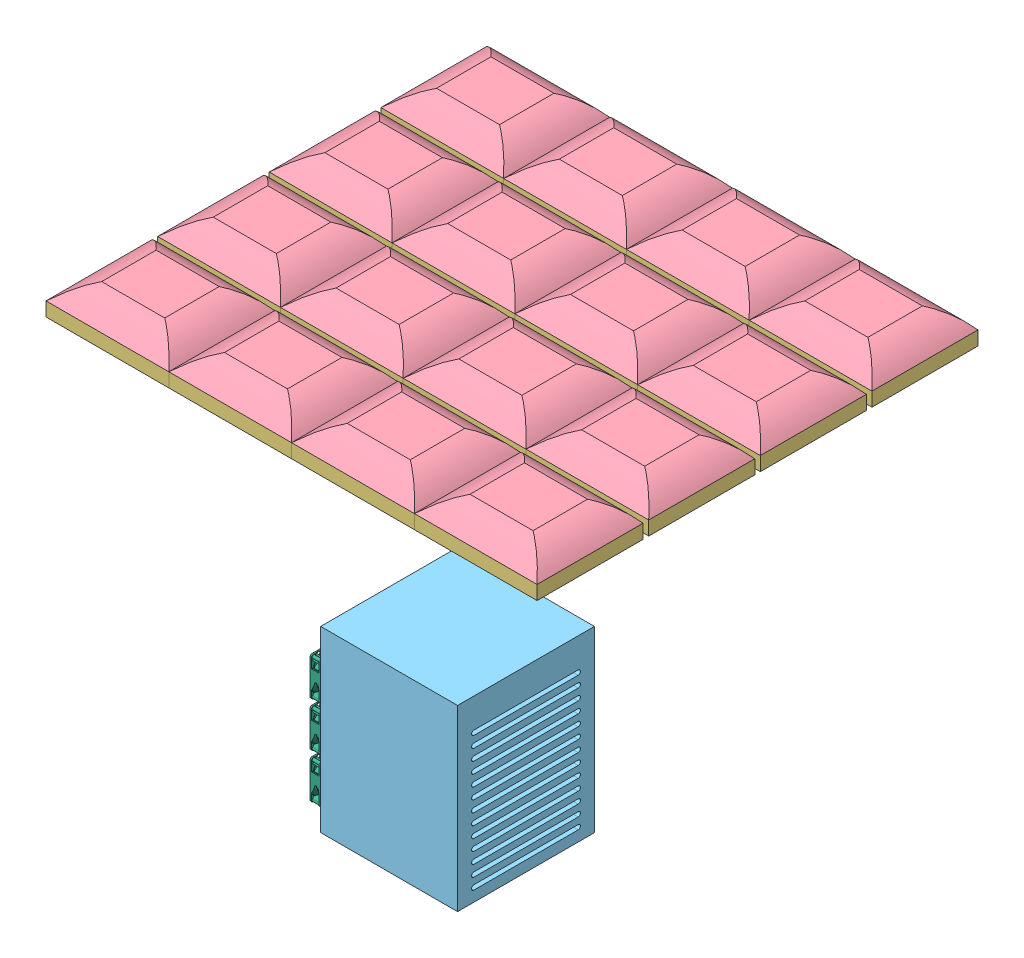
SolidWorks assembly Сборка2, configuration По умолчанию. Lengths in mm.
Overall size (44 41.09 39.5).
203 component instances, 7 part files, 2 mates.
Components (placement in the parent):
- Сборка1-8: Сборка1 [По умолчанию] at (6.9348 -5.2924 17.6089) size (11 2.93 9.5)
  - Ntrcnjkbn-1: Ntrcnjkbn [По умолчанию] at (-3.4337 12.5234 -9.2376) size (10.5 0.3 9)
  - Антенна-1: Антенна [По умолчанию] at (-7.1837 12.8234 -11.7376) size (2 0.4 3.88)
  - Антенна-2: Антенна [По умолчанию] at (-4.6837 12.8234 -11.7376) size (2 0.4 3.88)
  - Антенна-3: Антенна [По умолчанию] at (-2.1837 12.8234 -11.7376) size (2 0.4 3.88)
  - Антенна-4: Антенна [По умолчанию] at (0.3163 12.8234 -11.7376) size (2 0.4 3.88)
  - Антенна-5: Антенна [По умолчанию] at (0.3163 12.8234 -6.7376) x (-1 0 0) z (0 0 -1) size (2 0.4 3.88)
  - Антенна-6: Антенна [По умолчанию] at (-2.1837 12.8234 -6.7376) x (-1 0 0) z (0 0 -1) size (2 0.4 3.88)
  - Антенна-7: Антенна [По умолчанию] at (-4.6837 12.8234 -6.7376) x (-1 0 0) z (0 0 -1) size (2 0.4 3.88)
  - Антенна-8: Антенна [По умолчанию] at (-7.1837 12.8234 -6.7376) x (-1 0 0) z (0 0 -1) size (2 0.4 3.88)
  - Корпус-1: Корпус [По умолчанию] at (-3.4337 11.7734 -9.2035) size (11 1.25 9.5)
  - Крышка-1: Крышка [По умолчанию] at (-3.4337 13.0234 -9.2035) size (11 1.68 9.5)
- Сборка1-9: Сборка1 [По умолчанию] at (6.9348 -5.2924 27.6089) size (11 2.93 9.5)
  - Ntrcnjkbn-1: Ntrcnjkbn [По умолчанию] at (-3.4337 12.5234 -9.2376) size (10.5 0.3 9)
  - Антенна-1: Антенна [По умолчанию] at (-7.1837 12.8234 -11.7376) size (2 0.4 3.88)
  - Антенна-2: Антенна [По умолчанию] at (-4.6837 12.8234 -11.7376) size (2 0.4 3.88)
  - Антенна-3: Антенна [По умолчанию] at (-2.1837 12.8234 -11.7376) size (2 0.4 3.88)
  - Антенна-4: Антенна [По умолчанию] at (0.3163 12.8234 -11.7376) size (2 0.4 3.88)
  - Антенна-5: Антенна [По умолчанию] at (0.3163 12.8234 -6.7376) x (-1 0 0) z (0 0 -1) size (2 0.4 3.88)
  - Антенна-6: Антенна [По умолчанию] at (-2.1837 12.8234 -6.7376) x (-1 0 0) z (0 0 -1) size (2 0.4 3.88)
  - Антенна-7: Антенна [По умолчанию] at (-4.6837 12.8234 -6.7376) x (-1 0 0) z (0 0 -1) size (2 0.4 3.88)
  - Антенна-8: Антенна [По умолчанию] at (-7.1837 12.8234 -6.7376) x (-1 0 0) z (0 0 -1) size (2 0.4 3.88)
  - Корпус-1: Корпус [По умолчанию] at (-3.4337 11.7734 -9.2035) size (11 1.25 9.5)
  - Крышка-1: Крышка [По умолчанию] at (-3.4337 13.0234 -9.2035) size (11 1.68 9.5)
- Сборка1-10: Сборка1 [По умолчанию] at (6.9348 -5.2924 37.6089) size (11 2.93 9.5)
  - Ntrcnjkbn-1: Ntrcnjkbn [По умолчанию] at (-3.4337 12.5234 -9.2376) size (10.5 0.3 9)
  - Антенна-1: Антенна [По умолчанию] at (-7.1837 12.8234 -11.7376) size (2 0.4 3.88)
  - Антенна-2: Антенна [По умолчанию] at (-4.6837 12.8234 -11.7376) size (2 0.4 3.88)
  - Антенна-3: Антенна [По умолчанию] at (-2.1837 12.8234 -11.7376) size (2 0.4 3.88)
  - Антенна-4: Антенна [По умолчанию] at (0.3163 12.8234 -11.7376) size (2 0.4 3.88)
  - Антенна-5: Антенна [По умолчанию] at (0.3163 12.8234 -6.7376) x (-1 0 0) z (0 0 -1) size (2 0.4 3.88)
  - Антенна-6: Антенна [По умолчанию] at (-2.1837 12.8234 -6.7376) x (-1 0 0) z (0 0 -1) size (2 0.4 3.88)
  - Антенна-7: Антенна [По умолчанию] at (-4.6837 12.8234 -6.7376) x (-1 0 0) z (0 0 -1) size (2 0.4 3.88)
  - Антенна-8: Антенна [По умолчанию] at (-7.1837 12.8234 -6.7376) x (-1 0 0) z (0 0 -1) size (2 0.4 3.88)
  - Корпус-1: Корпус [По умолчанию] at (-3.4337 11.7734 -9.2035) size (11 1.25 9.5)
  - Крышка-1: Крышка [По умолчанию] at (-3.4337 13.0234 -9.2035) size (11 1.68 9.5)
- Сборка1-11: Сборка1 [По умолчанию] at (6.9348 -5.2924 47.6089) size (11 2.93 9.5)
  - Ntrcnjkbn-1: Ntrcnjkbn [По умолчанию] at (-3.4337 12.5234 -9.2376) size (10.5 0.3 9)
  - Антенна-1: Антенна [По умолчанию] at (-7.1837 12.8234 -11.7376) size (2 0.4 3.88)
  - Антенна-2: Антенна [По умолчанию] at (-4.6837 12.8234 -11.7376) size (2 0.4 3.88)
  - Антенна-3: Антенна [По умолчанию] at (-2.1837 12.8234 -11.7376) size (2 0.4 3.88)
  - Антенна-4: Антенна [По умолчанию] at (0.3163 12.8234 -11.7376) size (2 0.4 3.88)
  - Антенна-5: Антенна [По умолчанию] at (0.3163 12.8234 -6.7376) x (-1 0 0) z (0 0 -1) size (2 0.4 3.88)
  - Антенна-6: Антенна [По умолчанию] at (-2.1837 12.8234 -6.7376) x (-1 0 0) z (0 0 -1) size (2 0.4 3.88)
  - Антенна-7: Антенна [По умолчанию] at (-4.6837 12.8234 -6.7376) x (-1 0 0) z (0 0 -1) size (2 0.4 3.88)
  - Антенна-8: Антенна [По умолчанию] at (-7.1837 12.8234 -6.7376) x (-1 0 0) z (0 0 -1) size (2 0.4 3.88)
  - Корпус-1: Корпус [По умолчанию] at (-3.4337 11.7734 -9.2035) size (11 1.25 9.5)
  - Крышка-1: Крышка [По умолчанию] at (-3.4337 13.0234 -9.2035) size (11 1.68 9.5)
- Сборка1-12: Сборка1 [По умолчанию] at (17.9348 -5.2924 17.6089) size (11 2.93 9.5)
  - Ntrcnjkbn-1: Ntrcnjkbn [По умолчанию] at (-3.4337 12.5234 -9.2376) size (10.5 0.3 9)
  - Антенна-1: Антенна [По умолчанию] at (-7.1837 12.8234 -11.7376) size (2 0.4 3.88)
  - Антенна-2: Антенна [По умолчанию] at (-4.6837 12.8234 -11.7376) size (2 0.4 3.88)
  - Антенна-3: Антенна [По умолчанию] at (-2.1837 12.8234 -11.7376) size (2 0.4 3.88)
  - Антенна-4: Антенна [По умолчанию] at (0.3163 12.8234 -11.7376) size (2 0.4 3.88)
  - Антенна-5: Антенна [По умолчанию] at (0.3163 12.8234 -6.7376) x (-1 0 0) z (0 0 -1) size (2 0.4 3.88)
  - Антенна-6: Антенна [По умолчанию] at (-2.1837 12.8234 -6.7376) x (-1 0 0) z (0 0 -1) size (2 0.4 3.88)
  - Антенна-7: Антенна [По умолчанию] at (-4.6837 12.8234 -6.7376) x (-1 0 0) z (0 0 -1) size (2 0.4 3.88)
  - Антенна-8: Антенна [По умолчанию] at (-7.1837 12.8234 -6.7376) x (-1 0 0) z (0 0 -1) size (2 0.4 3.88)
  - Корпус-1: Корпус [По умолчанию] at (-3.4337 11.7734 -9.2035) size (11 1.25 9.5)
  - Крышка-1: Крышка [По умолчанию] at (-3.4337 13.0234 -9.2035) size (11 1.68 9.5)
- Сборка1-13: Сборка1 [По умолчанию] at (17.9348 -5.2924 27.6089) size (11 2.93 9.5)
  - Ntrcnjkbn-1: Ntrcnjkbn [По умолчанию] at (-3.4337 12.5234 -9.2376) size (10.5 0.3 9)
  - Антенна-1: Антенна [По умолчанию] at (-7.1837 12.8234 -11.7376) size (2 0.4 3.88)
  - Антенна-2: Антенна [По умолчанию] at (-4.6837 12.8234 -11.7376) size (2 0.4 3.88)
  - Антенна-3: Антенна [По умолчанию] at (-2.1837 12.8234 -11.7376) size (2 0.4 3.88)
  - Антенна-4: Антенна [По умолчанию] at (0.3163 12.8234 -11.7376) size (2 0.4 3.88)
  - Антенна-5: Антенна [По умолчанию] at (0.3163 12.8234 -6.7376) x (-1 0 0) z (0 0 -1) size (2 0.4 3.88)
  - Антенна-6: Антенна [По умолчанию] at (-2.1837 12.8234 -6.7376) x (-1 0 0) z (0 0 -1) size (2 0.4 3.88)
  - Антенна-7: Антенна [По умолчанию] at (-4.6837 12.8234 -6.7376) x (-1 0 0) z (0 0 -1) size (2 0.4 3.88)
  - Антенна-8: Антенна [По умолчанию] at (-7.1837 12.8234 -6.7376) x (-1 0 0) z (0 0 -1) size (2 0.4 3.88)
  - Корпус-1: Корпус [По умолчанию] at (-3.4337 11.7734 -9.2035) size (11 1.25 9.5)
  - Крышка-1: Крышка [По умолчанию] at (-3.4337 13.0234 -9.2035) size (11 1.68 9.5)
- Сборка1-14: Сборка1 [По умолчанию] at (17.9348 -5.2924 37.6089) size (11 2.93 9.5)
  - Ntrcnjkbn-1: Ntrcnjkbn [По умолчанию] at (-3.4337 12.5234 -9.2376) size (10.5 0.3 9)
  - Антенна-1: Антенна [По умолчанию] at (-7.1837 12.8234 -11.7376) size (2 0.4 3.88)
  - Антенна-2: Антенна [По умолчанию] at (-4.6837 12.8234 -11.7376) size (2 0.4 3.88)
  - Антенна-3: Антенна [По умолчанию] at (-2.1837 12.8234 -11.7376) size (2 0.4 3.88)
  - Антенна-4: Антенна [По умолчанию] at (0.3163 12.8234 -11.7376) size (2 0.4 3.88)
  - Антенна-5: Антенна [По умолчанию] at (0.3163 12.8234 -6.7376) x (-1 0 0) z (0 0 -1) size (2 0.4 3.88)
  - Антенна-6: Антенна [По умолчанию] at (-2.1837 12.8234 -6.7376) x (-1 0 0) z (0 0 -1) size (2 0.4 3.88)
  - Антенна-7: Антенна [По умолчанию] at (-4.6837 12.8234 -6.7376) x (-1 0 0) z (0 0 -1) size (2 0.4 3.88)
  - Антенна-8: Антенна [По умолчанию] at (-7.1837 12.8234 -6.7376) x (-1 0 0) z (0 0 -1) size (2 0.4 3.88)
  - Корпус-1: Корпус [По умолчанию] at (-3.4337 11.7734 -9.2035) size (11 1.25 9.5)
  - Крышка-1: Крышка [По умолчанию] at (-3.4337 13.0234 -9.2035) size (11 1.68 9.5)
- Сборка1-15: Сборка1 [По умолчанию] at (17.9348 -5.2924 47.6089) size (11 2.93 9.5)
  - Ntrcnjkbn-1: Ntrcnjkbn [По умолчанию] at (-3.4337 12.5234 -9.2376) size (10.5 0.3 9)
  - Антенна-1: Антенна [По умолчанию] at (-7.1837 12.8234 -11.7376) size (2 0.4 3.88)
  - Антенна-2: Антенна [По умолчанию] at (-4.6837 12.8234 -11.7376) size (2 0.4 3.88)
  - Антенна-3: Антенна [По умолчанию] at (-2.1837 12.8234 -11.7376) size (2 0.4 3.88)
  - Антенна-4: Антенна [По умолчанию] at (0.3163 12.8234 -11.7376) size (2 0.4 3.88)
  - Антенна-5: Антенна [По умолчанию] at (0.3163 12.8234 -6.7376) x (-1 0 0) z (0 0 -1) size (2 0.4 3.88)
  - Антенна-6: Антенна [По умолчанию] at (-2.1837 12.8234 -6.7376) x (-1 0 0) z (0 0 -1) size (2 0.4 3.88)
  - Антенна-7: Антенна [По умолчанию] at (-4.6837 12.8234 -6.7376) x (-1 0 0) z (0 0 -1) size (2 0.4 3.88)
  - Антенна-8: Антенна [По умолчанию] at (-7.1837 12.8234 -6.7376) x (-1 0 0) z (0 0 -1) size (2 0.4 3.88)
  - Корпус-1: Корпус [По умолчанию] at (-3.4337 11.7734 -9.2035) size (11 1.25 9.5)
  - Крышка-1: Крышка [По умолчанию] at (-3.4337 13.0234 -9.2035) size (11 1.68 9.5)
- Сборка1-16: Сборка1 [По умолчанию] at (28.9348 -5.2924 17.6089) size (11 2.93 9.5)
  - Ntrcnjkbn-1: Ntrcnjkbn [По умолчанию] at (-3.4337 12.5234 -9.2376) size (10.5 0.3 9)
  - Антенна-1: Антенна [По умолчанию] at (-7.1837 12.8234 -11.7376) size (2 0.4 3.88)
  - Антенна-2: Антенна [По умолчанию] at (-4.6837 12.8234 -11.7376) size (2 0.4 3.88)
  - Антенна-3: Антенна [По умолчанию] at (-2.1837 12.8234 -11.7376) size (2 0.4 3.88)
  - Антенна-4: Антенна [По умолчанию] at (0.3163 12.8234 -11.7376) size (2 0.4 3.88)
  - Антенна-5: Антенна [По умолчанию] at (0.3163 12.8234 -6.7376) x (-1 0 0) z (0 0 -1) size (2 0.4 3.88)
  - Антенна-6: Антенна [По умолчанию] at (-2.1837 12.8234 -6.7376) x (-1 0 0) z (0 0 -1) size (2 0.4 3.88)
  - Антенна-7: Антенна [По умолчанию] at (-4.6837 12.8234 -6.7376) x (-1 0 0) z (0 0 -1) size (2 0.4 3.88)
  - Антенна-8: Антенна [По умолчанию] at (-7.1837 12.8234 -6.7376) x (-1 0 0) z (0 0 -1) size (2 0.4 3.88)
  - Корпус-1: Корпус [По умолчанию] at (-3.4337 11.7734 -9.2035) size (11 1.25 9.5)
  - Крышка-1: Крышка [По умолчанию] at (-3.4337 13.0234 -9.2035) size (11 1.68 9.5)
- Сборка1-17: Сборка1 [По умолчанию] at (28.9348 -5.2924 27.6089) size (11 2.93 9.5)
  - Ntrcnjkbn-1: Ntrcnjkbn [По умолчанию] at (-3.4337 12.5234 -9.2376) size (10.5 0.3 9)
  - Антенна-1: Антенна [По умолчанию] at (-7.1837 12.8234 -11.7376) size (2 0.4 3.88)
  - Антенна-2: Антенна [По умолчанию] at (-4.6837 12.8234 -11.7376) size (2 0.4 3.88)
  - Антенна-3: Антенна [По умолчанию] at (-2.1837 12.8234 -11.7376) size (2 0.4 3.88)
  - Антенна-4: Антенна [По умолчанию] at (0.3163 12.8234 -11.7376) size (2 0.4 3.88)
  - Антенна-5: Антенна [По умолчанию] at (0.3163 12.8234 -6.7376) x (-1 0 0) z (0 0 -1) size (2 0.4 3.88)
  - Антенна-6: Антенна [По умолчанию] at (-2.1837 12.8234 -6.7376) x (-1 0 0) z (0 0 -1) size (2 0.4 3.88)
  - Антенна-7: Антенна [По умолчанию] at (-4.6837 12.8234 -6.7376) x (-1 0 0) z (0 0 -1) size (2 0.4 3.88)
  - Антенна-8: Антенна [По умолчанию] at (-7.1837 12.8234 -6.7376) x (-1 0 0) z (0 0 -1) size (2 0.4 3.88)
  - Корпус-1: Корпус [По умолчанию] at (-3.4337 11.7734 -9.2035) size (11 1.25 9.5)
  - Крышка-1: Крышка [По умолчанию] at (-3.4337 13.0234 -9.2035) size (11 1.68 9.5)
- Сборка1-18: Сборка1 [По умолчанию] at (28.9348 -5.2924 37.6089) size (11 2.93 9.5)
  - Ntrcnjkbn-1: Ntrcnjkbn [По умолчанию] at (-3.4337 12.5234 -9.2376) size (10.5 0.3 9)
  - Антенна-1: Антенна [По умолчанию] at (-7.1837 12.8234 -11.7376) size (2 0.4 3.88)
  - Антенна-2: Антенна [По умолчанию] at (-4.6837 12.8234 -11.7376) size (2 0.4 3.88)
  - Антенна-3: Антенна [По умолчанию] at (-2.1837 12.8234 -11.7376) size (2 0.4 3.88)
  - Антенна-4: Антенна [По умолчанию] at (0.3163 12.8234 -11.7376) size (2 0.4 3.88)
  - Антенна-5: Антенна [По умолчанию] at (0.3163 12.8234 -6.7376) x (-1 0 0) z (0 0 -1) size (2 0.4 3.88)
  - Антенна-6: Антенна [По умолчанию] at (-2.1837 12.8234 -6.7376) x (-1 0 0) z (0 0 -1) size (2 0.4 3.88)
  - Антенна-7: Антенна [По умолчанию] at (-4.6837 12.8234 -6.7376) x (-1 0 0) z (0 0 -1) size (2 0.4 3.88)
  - Антенна-8: Антенна [По умолчанию] at (-7.1837 12.8234 -6.7376) x (-1 0 0) z (0 0 -1) size (2 0.4 3.88)
  - Корпус-1: Корпус [По умолчанию] at (-3.4337 11.7734 -9.2035) size (11 1.25 9.5)
  - Крышка-1: Крышка [По умолчанию] at (-3.4337 13.0234 -9.2035) size (11 1.68 9.5)
- Сборка1-19: Сборка1 [По умолчанию] at (28.9348 -5.2924 47.6089) size (11 2.93 9.5)
  - Ntrcnjkbn-1: Ntrcnjkbn [По умолчанию] at (-3.4337 12.5234 -9.2376) size (10.5 0.3 9)
  - Антенна-1: Антенна [По умолчанию] at (-7.1837 12.8234 -11.7376) size (2 0.4 3.88)
  - Антенна-2: Антенна [По умолчанию] at (-4.6837 12.8234 -11.7376) size (2 0.4 3.88)
  - Антенна-3: Антенна [По умолчанию] at (-2.1837 12.8234 -11.7376) size (2 0.4 3.88)
  - Антенна-4: Антенна [По умолчанию] at (0.3163 12.8234 -11.7376) size (2 0.4 3.88)
  - Антенна-5: Антенна [По умолчанию] at (0.3163 12.8234 -6.7376) x (-1 0 0) z (0 0 -1) size (2 0.4 3.88)
  - Антенна-6: Антенна [По умолчанию] at (-2.1837 12.8234 -6.7376) x (-1 0 0) z (0 0 -1) size (2 0.4 3.88)
  - Антенна-7: Антенна [По умолчанию] at (-4.6837 12.8234 -6.7376) x (-1 0 0) z (0 0 -1) size (2 0.4 3.88)
  - Антенна-8: Антенна [По умолчанию] at (-7.1837 12.8234 -6.7376) x (-1 0 0) z (0 0 -1) size (2 0.4 3.88)
  - Корпус-1: Корпус [По умолчанию] at (-3.4337 11.7734 -9.2035) size (11 1.25 9.5)
  - Крышка-1: Крышка [По умолчанию] at (-3.4337 13.0234 -9.2035) size (11 1.68 9.5)
- Сборка1-20: Сборка1 [По умолчанию] at (39.9348 -5.2924 17.6089) size (11 2.93 9.5)
  - Ntrcnjkbn-1: Ntrcnjkbn [По умолчанию] at (-3.4337 12.5234 -9.2376) size (10.5 0.3 9)
  - Антенна-1: Антенна [По умолчанию] at (-7.1837 12.8234 -11.7376) size (2 0.4 3.88)
  - Антенна-2: Антенна [По умолчанию] at (-4.6837 12.8234 -11.7376) size (2 0.4 3.88)
  - Антенна-3: Антенна [По умолчанию] at (-2.1837 12.8234 -11.7376) size (2 0.4 3.88)
  - Антенна-4: Антенна [По умолчанию] at (0.3163 12.8234 -11.7376) size (2 0.4 3.88)
  - Антенна-5: Антенна [По умолчанию] at (0.3163 12.8234 -6.7376) x (-1 0 0) z (0 0 -1) size (2 0.4 3.88)
  - Антенна-6: Антенна [По умолчанию] at (-2.1837 12.8234 -6.7376) x (-1 0 0) z (0 0 -1) size (2 0.4 3.88)
  - Антенна-7: Антенна [По умолчанию] at (-4.6837 12.8234 -6.7376) x (-1 0 0) z (0 0 -1) size (2 0.4 3.88)
  - Антенна-8: Антенна [По умолчанию] at (-7.1837 12.8234 -6.7376) x (-1 0 0) z (0 0 -1) size (2 0.4 3.88)
  - Корпус-1: Корпус [По умолчанию] at (-3.4337 11.7734 -9.2035) size (11 1.25 9.5)
  - Крышка-1: Крышка [По умолчанию] at (-3.4337 13.0234 -9.2035) size (11 1.68 9.5)
- Сборка1-21: Сборка1 [По умолчанию] at (39.9348 -5.2924 27.6089) size (11 2.93 9.5)
  - Ntrcnjkbn-1: Ntrcnjkbn [По умолчанию] at (-3.4337 12.5234 -9.2376) size (10.5 0.3 9)
  - Антенна-1: Антенна [По умолчанию] at (-7.1837 12.8234 -11.7376) size (2 0.4 3.88)
  - Антенна-2: Антенна [По умолчанию] at (-4.6837 12.8234 -11.7376) size (2 0.4 3.88)
  - Антенна-3: Антенна [По умолчанию] at (-2.1837 12.8234 -11.7376) size (2 0.4 3.88)
  - Антенна-4: Антенна [По умолчанию] at (0.3163 12.8234 -11.7376) size (2 0.4 3.88)
  - Антенна-5: Антенна [По умолчанию] at (0.3163 12.8234 -6.7376) x (-1 0 0) z (0 0 -1) size (2 0.4 3.88)
  - Антенна-6: Антенна [По умолчанию] at (-2.1837 12.8234 -6.7376) x (-1 0 0) z (0 0 -1) size (2 0.4 3.88)
  - Антенна-7: Антенна [По умолчанию] at (-4.6837 12.8234 -6.7376) x (-1 0 0) z (0 0 -1) size (2 0.4 3.88)
  - Антенна-8: Антенна [По умолчанию] at (-7.1837 12.8234 -6.7376) x (-1 0 0) z (0 0 -1) size (2 0.4 3.88)
  - Корпус-1: Корпус [По умолчанию] at (-3.4337 11.7734 -9.2035) size (11 1.25 9.5)
  - Крышка-1: Крышка [По умолчанию] at (-3.4337 13.0234 -9.2035) size (11 1.68 9.5)
- Сборка1-22: Сборка1 [По умолчанию] at (39.9348 -5.2924 37.6089) size (11 2.93 9.5)
  - Ntrcnjkbn-1: Ntrcnjkbn [По умолчанию] at (-3.4337 12.5234 -9.2376) size (10.5 0.3 9)
  - Антенна-1: Антенна [По умолчанию] at (-7.1837 12.8234 -11.7376) size (2 0.4 3.88)
  - Антенна-2: Антенна [По умолчанию] at (-4.6837 12.8234 -11.7376) size (2 0.4 3.88)
  - Антенна-3: Антенна [По умолчанию] at (-2.1837 12.8234 -11.7376) size (2 0.4 3.88)
  - Антенна-4: Антенна [По умолчанию] at (0.3163 12.8234 -11.7376) size (2 0.4 3.88)
  - Антенна-5: Антенна [По умолчанию] at (0.3163 12.8234 -6.7376) x (-1 0 0) z (0 0 -1) size (2 0.4 3.88)
  - Антенна-6: Антенна [По умолчанию] at (-2.1837 12.8234 -6.7376) x (-1 0 0) z (0 0 -1) size (2 0.4 3.88)
  - Антенна-7: Антенна [По умолчанию] at (-4.6837 12.8234 -6.7376) x (-1 0 0) z (0 0 -1) size (2 0.4 3.88)
  - Антенна-8: Антенна [По умолчанию] at (-7.1837 12.8234 -6.7376) x (-1 0 0) z (0 0 -1) size (2 0.4 3.88)
  - Корпус-1: Корпус [По умолчанию] at (-3.4337 11.7734 -9.2035) size (11 1.25 9.5)
  - Крышка-1: Крышка [По умолчанию] at (-3.4337 13.0234 -9.2035) size (11 1.68 9.5)
- Сборка1-23: Сборка1 [По умолчанию] at (39.9348 -5.2924 47.6089) size (11 2.93 9.5)
  - Ntrcnjkbn-1: Ntrcnjkbn [По умолчанию] at (-3.4337 12.5234 -9.2376) size (10.5 0.3 9)
  - Антенна-1: Антенна [По умолчанию] at (-7.1837 12.8234 -11.7376) size (2 0.4 3.88)
  - Антенна-2: Антенна [По умолчанию] at (-4.6837 12.8234 -11.7376) size (2 0.4 3.88)
  - Антенна-3: Антенна [По умолчанию] at (-2.1837 12.8234 -11.7376) size (2 0.4 3.88)
  - Антенна-4: Антенна [По умолчанию] at (0.3163 12.8234 -11.7376) size (2 0.4 3.88)
  - Антенна-5: Антенна [По умолчанию] at (0.3163 12.8234 -6.7376) x (-1 0 0) z (0 0 -1) size (2 0.4 3.88)
  - Антенна-6: Антенна [По умолчанию] at (-2.1837 12.8234 -6.7376) x (-1 0 0) z (0 0 -1) size (2 0.4 3.88)
  - Антенна-7: Антенна [По умолчанию] at (-4.6837 12.8234 -6.7376) x (-1 0 0) z (0 0 -1) size (2 0.4 3.88)
  - Антенна-8: Антенна [По умолчанию] at (-7.1837 12.8234 -6.7376) x (-1 0 0) z (0 0 -1) size (2 0.4 3.88)
  - Корпус-1: Корпус [По умолчанию] at (-3.4337 11.7734 -9.2035) size (11 1.25 9.5)
  - Крышка-1: Крышка [По умолчанию] at (-3.4337 13.0234 -9.2035) size (11 1.68 9.5)
- Деталь1^Сборка2-1: Деталь1^Сборка2 [По умолчанию] at (-39.0674 -9.8745 -12.8076) x (-1 0 0) z (0 -1 0) size (12.26 12.26 16) (virtual)
- Деталь3^Сборка2-1: Деталь3^Сборка2 [По умолчанию] at origin (virtual)
- User Library-ex-00000-002-1: User Library-ex-00000-002 [Default] at (12.1515 -20.0514 30.971) x (0 0 1) z (-1 0 0) size (3.45 3.45 1.31)
- User Library-ex-00000-002-2: User Library-ex-00000-002 [Default] at (12.1515 -20.0514 26.971) x (0 0 1) z (-1 0 0) size (3.45 3.45 1.31)
- User Library-ex-00000-002-3: User Library-ex-00000-002 [Default] at (12.1515 -20.0514 22.971) x (0 0 1) z (-1 0 0) size (3.45 3.45 1.31)
- User Library-ex-00000-002-4: User Library-ex-00000-002 [Default] at (12.1515 -24.0514 30.971) x (0 0 1) z (-1 0 0) size (3.45 3.45 1.31)
- User Library-ex-00000-002-5: User Library-ex-00000-002 [Default] at (12.1515 -24.0514 26.971) x (0 0 1) z (-1 0 0) size (3.45 3.45 1.31)
- User Library-ex-00000-002-6: User Library-ex-00000-002 [Default] at (12.1515 -24.0514 22.971) x (0 0 1) z (-1 0 0) size (3.45 3.45 1.31)
- User Library-ex-00000-002-7: User Library-ex-00000-002 [Default] at (12.1515 -28.0514 30.971) x (0 0 1) z (-1 0 0) size (3.45 3.45 1.31)
- User Library-ex-00000-002-8: User Library-ex-00000-002 [Default] at (12.1515 -28.0514 26.971) x (0 0 1) z (-1 0 0) size (3.45 3.45 1.31)
- User Library-ex-00000-002-9: User Library-ex-00000-002 [Default] at (12.1515 -28.0514 22.971) x (0 0 1) z (-1 0 0) size (3.45 3.45 1.31)
Mates (geometry in assembly coordinates):
- Совпадение12: coincident anti-aligned: line of Деталь1^Сборка2-1 through (12.1515 -18.3274 21.8917) axis (0 0 1); line of User Library-ex-00000-002-1 through (12.1515 -18.3274 31.9502) axis (0 0 -1)
- Совпадение13: coincident anti-aligned: line of Деталь1^Сборка2-1 through (12.1515 -15.6816 32.695) axis (0 -1 0); line of User Library-ex-00000-002-1 through (12.1515 -21.6266 32.695) axis (0 1 0)
